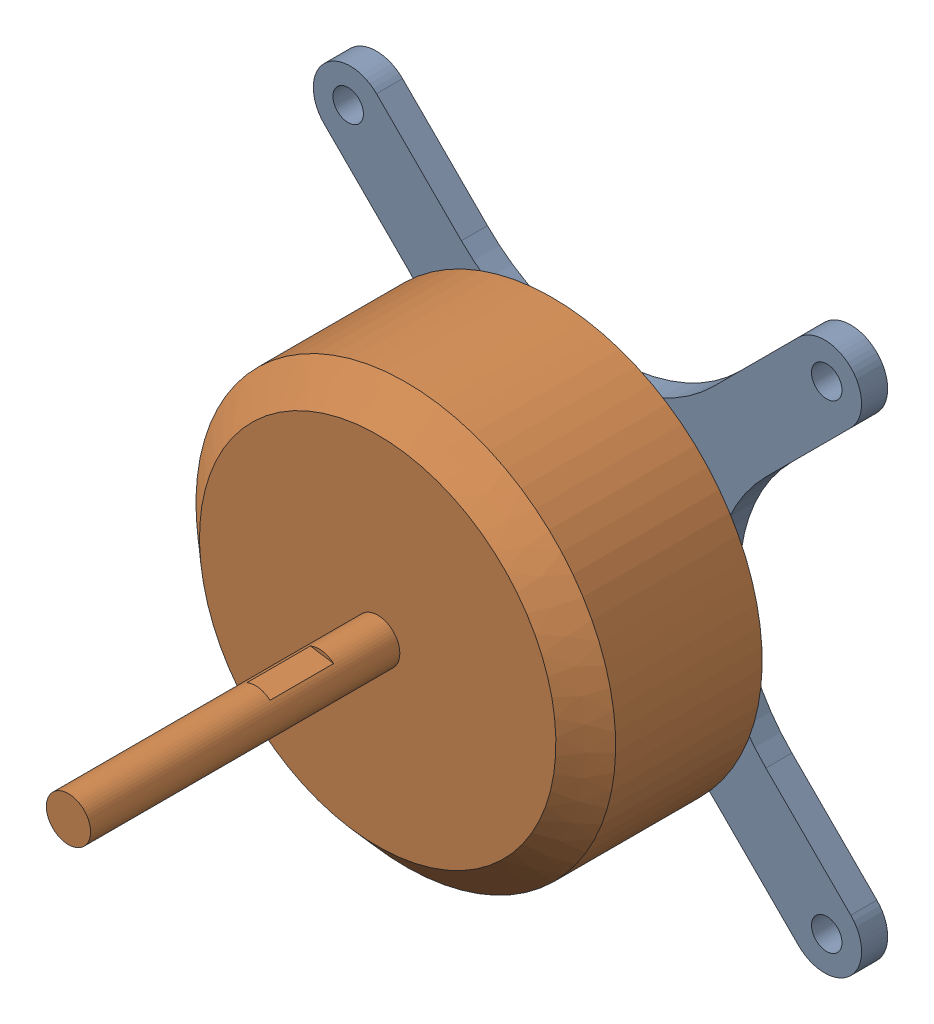
SolidWorks assembly Motor, configuration Default. Lengths in mm.
Overall size (37.43 37.43 38.34).
2 component instances, 2 part files, 2 mates.
Components (placement in the parent):
- Mount-1: Mount [Default] at origin size (37.43 37.43 8.78)
- Rotor-1: Rotor [Default] at (0 0 4.18) x (-0.155389 -0.987853 0) z (0 0 1) size (28.65 28.65 38.34)
Mates (geometry in assembly coordinates):
- Concentric1: concentric aligned: circle of Mount-1; circle of Rotor-1
- Distance1: distance = 2.4 mm anti-aligned: plane of Rotor-1 through (0 0 4.18) normal (0 0 -1); plane of Mount-1 through (0 0 1.78) normal (0 0 1)
